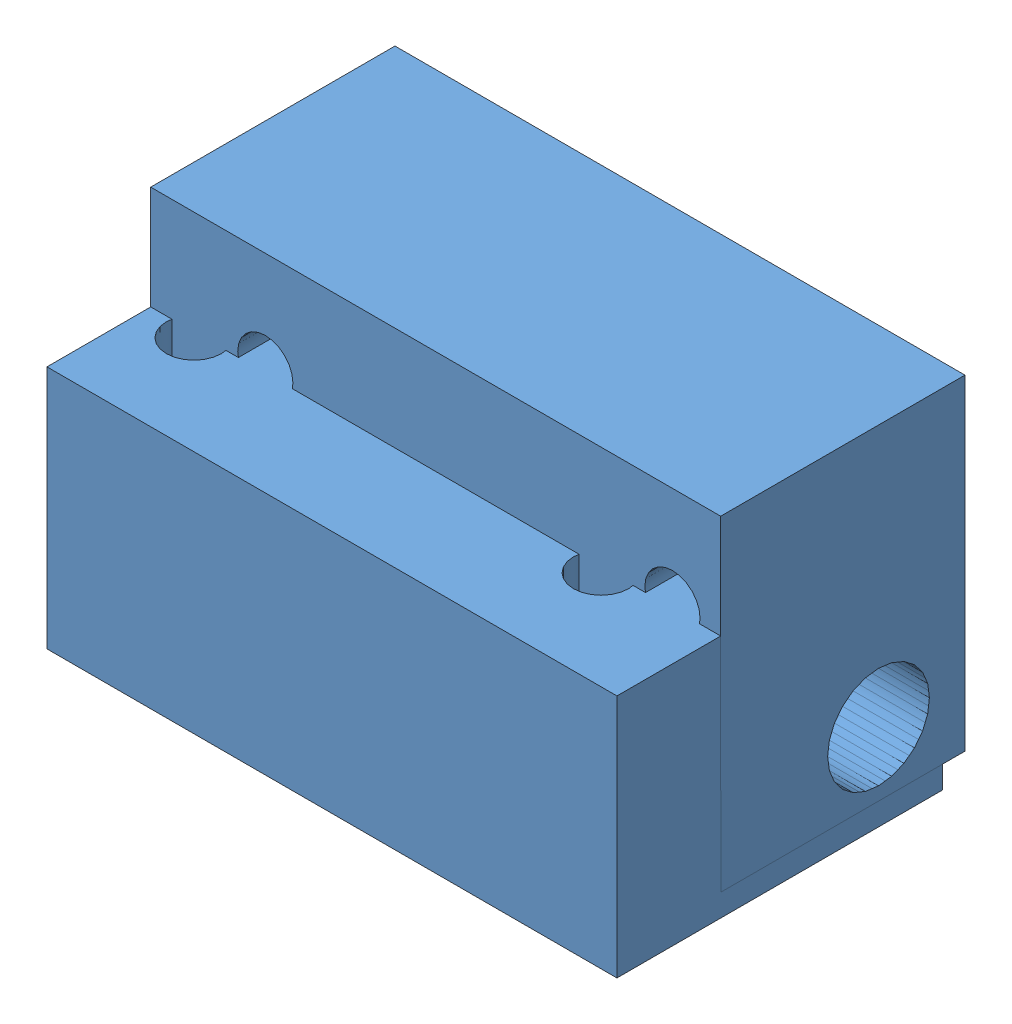
SolidWorks assembly Hinge1, configuration Default. Lengths in mm.
Overall size (44.45 27.15 27.15).
3 component instances, 2 part files, 3 mates.
Components (placement in the parent):
- Hinge2-1: Hinge2 [Default] at (39.8063 -5.4183 -30.6651) size (44.45 12.7 25.4)
- Rod1-1: Rod1 [Default] at (-16.8889 1.3286 -6.1216) x (0 0 -1) z (1 0 0) size (7.94 7.94 25.4)
- Hinge2-2: Hinge2 [Default] at (-29.1342 -23.2133 -12.8745) x (-1 0 0) z (0 1 0.000244) size (44.45 12.7 25.4)
Mates (geometry in assembly coordinates):
- Concentric3: concentric anti-aligned: circle of Rod1-1; circle of Hinge2-2
- Coincident6: coincident aligned: plane of Hinge2-1 through (-16.8889 7.2817 -11.1225) normal (-1 0 0); plane of Hinge2-2 through (-16.8889 -3.6738 -0.1697) normal (-1 0 0)
- Concentric4: concentric aligned: circle of Hinge2-1; circle of Hinge2-2
